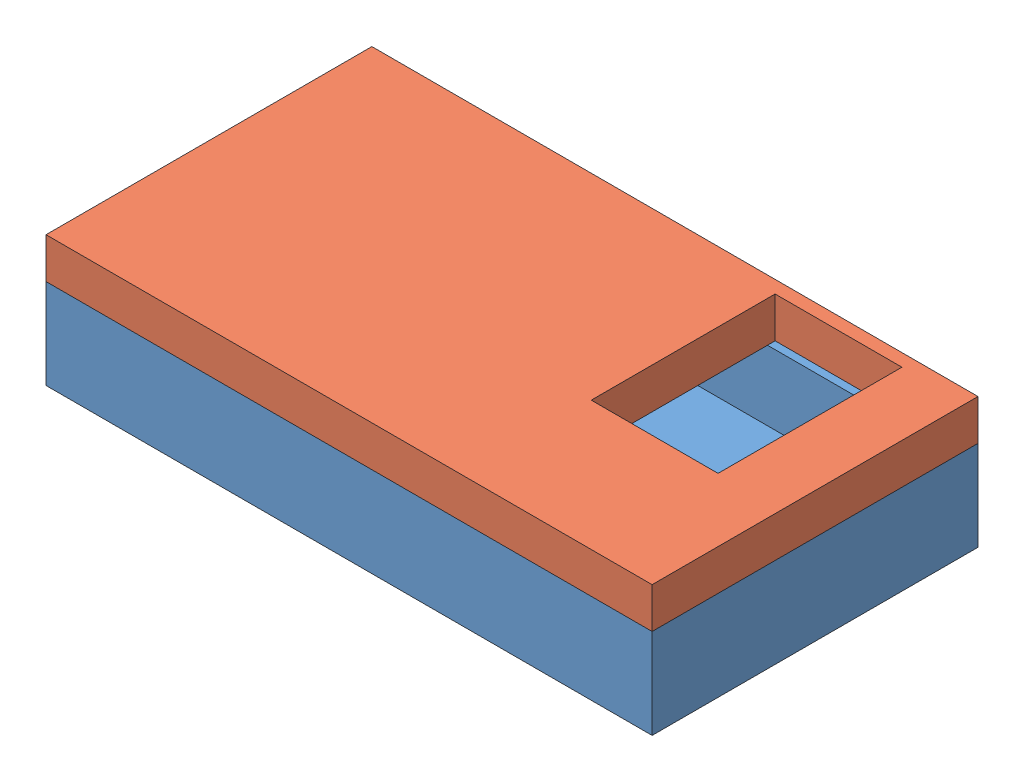
SolidWorks assembly Assieme2, configuration Default. Lengths in mm.
Overall size (47.8 10.3 25.7).
2 component instances, 2 part files, 2 mates.
Components (placement in the parent):
- baseUSB-1: baseUSB [Default] at (0.2558 2.1144 0) size (47.8 7.1 25.7)
- coperchioUSB-1: coperchioUSB [Default] at (0.2558 12.4144 0) x (-1 0 0) z (0 0 1) size (47.8 7.7 25.7)
Mates (geometry in assembly coordinates):
- Coincidente3: coincident anti-aligned: line of baseUSB-1 through (24.1558 9.2144 -12.85) axis (-1 0 0); line of coperchioUSB-1 through (-23.6442 9.2144 -12.85) axis (1 0 0)
- Coincidente4: coincident anti-aligned: line of baseUSB-1 through (24.1558 9.2144 12.85) axis (0 0 -1); line of coperchioUSB-1 through (24.1558 9.2144 -12.85) axis (0 0 1)
